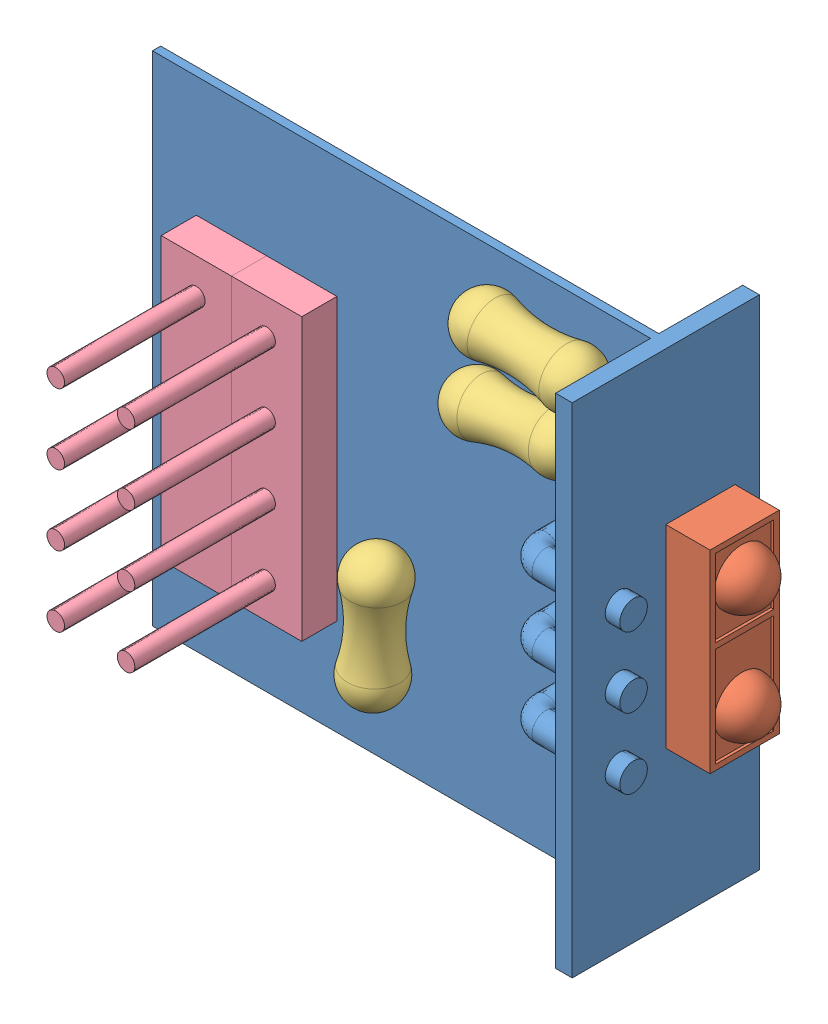
SolidWorks assembly Sensor_prox, configuration Default. Lengths in mm.
Overall size (21.1 18 9.68).
7 component instances, 4 part files, 15 mates.
Components (placement in the parent):
- PCB_prox-1: PCB_prox [Default] at origin size (19.13 18 6.76)
- sensor_prox-1: sensor_prox [Default] at (0.6 0 -1.0505) x (0 1 0) z (1 0 0) size (7 2.5 2.5)
- resistência-1: resistência [Default] at (-3.3746 7.4242 1.1455) x (-0.998687 0.051224 0) z (-0.001015 -0.019788 -0.999804) size (5.08 1.99 1.99)
- resistência-2: resistência [Default] at (-3.7432 4.985 1.1455) x (0.994768 0.102156 0) z (-0.09564 0.931323 -0.351413) size (5.08 1.99 1.99)
- resistência-3: resistência [Default] at (-8.9777 -3.9893 1.1455) x (0.039322 0.999227 0) z (0.675563 -0.026585 0.736823) size (5.08 1.99 1.99)
- conector_4pinos_macho-1: conector_4pinos_macho [Default] at (-15.1425 -0.4323 0.15) x (0 -1 0) z (-1 0 0) size (10.16 7.62 2.54)
- conector_4pinos_macho-2: conector_4pinos_macho [Default] at (-12.6025 -0.4323 0.15) x (0 -1 0) z (-1 0 0) size (10.16 7.62 2.54)
Mates (geometry in assembly coordinates):
- Coincident1: coincident anti-aligned: plane of PCB_prox-1 through (0.6 9 3.5805) normal (1 0 0); plane of sensor_prox-1 through (0.6 -3.5 -2.3005) normal (-1 0 0)
- Distance2: distance = 3.381 mm aligned: plane of PCB_prox-1 through (0.6 -9 3.5805) normal (0 0 1); plane of sensor_prox-1 through (2.1 -3.5 0.1995) normal (0 0 1)
- Width1: width: plane of PCB_prox-1 through (-18 -9 0.15) normal (0 -1 0); plane of PCB_prox-1 through (-18 9 0.15) normal (0 1 0); plane of sensor_prox-1 through (2.1 3.5 0.1995) normal (0 1 0); plane of sensor_prox-1 through (2.1 -3.5 0.1995) normal (0 -1 0)
- Tangent1: tangent anti-aligned: plane of PCB_prox-1 through (-18 9 0.15) normal (0 0 1); sphere of resistência-1
- Tangent2: tangent anti-aligned: plane of PCB_prox-1 through (-18 9 0.15) normal (0 0 1); sphere of resistência-1
- Tangent3: tangent anti-aligned: plane of PCB_prox-1 through (-18 9 0.15) normal (0 0 1); sphere of resistência-2
- Tangent4: tangent anti-aligned: plane of PCB_prox-1 through (-18 9 0.15) normal (0 0 1); sphere of resistência-2
- Tangent5: tangent anti-aligned: plane of PCB_prox-1 through (-18 9 0.15) normal (0 0 1); sphere of resistência-3
- Tangent6: tangent anti-aligned: plane of PCB_prox-1 through (-18 9 0.15) normal (0 0 1); sphere of resistência-3
- Coincident3: coincident anti-aligned: plane of PCB_prox-1 through (-18 9 0.15) normal (0 0 1); plane of conector_4pinos_macho-1 through (-16.4125 4.6477 0.15) normal (0 0 -1)
- Distance3: distance = 2.54 mm aligned: plane of PCB_prox-1 through (-18 -9 0.15) normal (-1 0 0); cylinder of conector_4pinos_macho-1
- Distance4: distance = 2.54 mm aligned: plane of PCB_prox-1 through (-18 -9 0.15) normal (-1 0 0); cylinder of conector_4pinos_macho-1
- Coincident4: coincident anti-aligned: plane of PCB_prox-1 through (-18 9 0.15) normal (0 0 1); plane of conector_4pinos_macho-2 through (-13.8725 4.6477 0.15) normal (0 0 -1)
- Coincident5: coincident anti-aligned: plane of conector_4pinos_macho-1 through (-13.8725 4.6477 1.42) normal (1 0 0); plane of conector_4pinos_macho-2 through (-13.8725 4.6477 1.42) normal (-1 0 0)
- Coincident6: coincident aligned: plane of conector_4pinos_macho-1 through (-13.8725 -5.5123 1.42) normal (0 -1 0); plane of conector_4pinos_macho-2 through (-11.3325 -5.5123 1.42) normal (0 -1 0)
